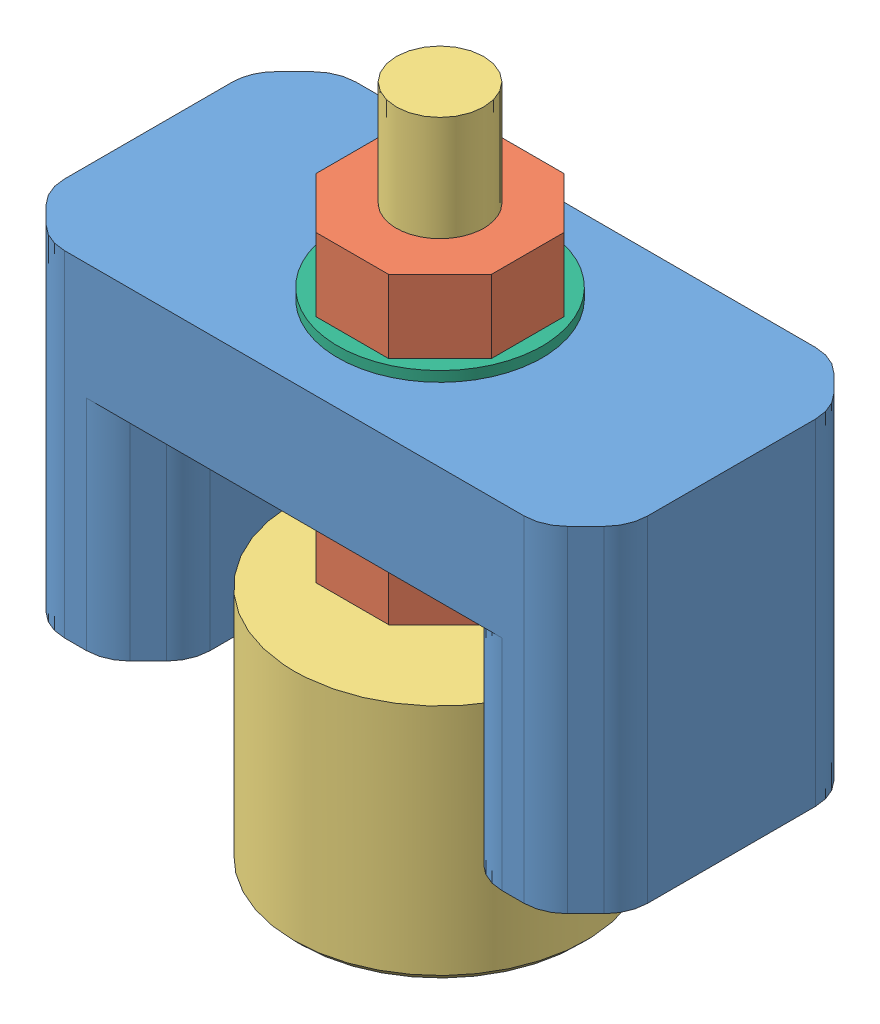
SolidWorks assembly Assemblage Roue Porteuse, configuration Défaut. Lengths in mm.
Overall size (40 50.71 20).
11 component instances, 6 part files, 20 mates.
Components (placement in the parent):
- Support Bille porteuse-1: Support Bille porteuse [Défaut] at (1.9744 -30.0894 -26.9817) size (40 23 20)
- Ecrou M6-3: Ecrou M6 [Défaut] at (1.9744 -17.1894 -26.9817) x (1 0 0) z (0 -1 0) size (12 12 5)
- Ecrou M6-2: Ecrou M6 [Défaut] at (1.9744 -1.3894 -26.9817) x (1 0 0) z (0 -1 0) size (12 12 5)
- Bille porteuse ALWAYE D12_7-2: Bille porteuse ALWAYE D12_7 [Défaut] at (1.9744 -30.1894 -26.9817) size (20 46.5 20)
- Bille D12-2: Bille D12 [Défaut] at (1.9744 -38.8998 -26.9817) size (12 12 12)
- Insert M4-2: Insert M4 [Défaut] at (16.9744 -30.0894 -26.9817) x (-0.837169 0 -0.546944) z (0 1 0) size (7 7 8)
- Insert M4-3: Insert M4 [Défaut] at (-13.0256 -30.0894 -26.9817) x (-0.837169 0 -0.546944) z (0 1 0) size (7 7 8)
- Rondelle M6-6: Rondelle M6 [Défaut] at (1.9744 -17.1894 -26.9817) x (1 0 0) z (0 1 0) size (14 14 0.7)
- Rondelle M6-7: Rondelle M6 [Défaut] at (1.9744 -16.4894 -26.9817) x (1 0 0) z (0 1 0) size (14 14 0.7)
- Rondelle M6-5: Rondelle M6 [Défaut] at (1.9744 -15.7894 -26.9817) x (1 0 0) z (0 1 0) size (14 14 0.7)
- Rondelle M6-4: Rondelle M6 [Défaut] at (1.9744 -7.0894 -26.9817) x (1 0 0) z (0 1 0) size (14 14 0.7)
Mates (geometry in assembly coordinates):
- Coaxiale9: concentric: cylinder of Bille porteuse ALWAYE D12_7-2 through (1.9744 -40.1894 -26.9817) axis (0 1 0) radius 6.75; sphere of Bille D12-2
- Verrouiller1: lock: unknown of Bille porteuse ALWAYE D12_7-2; unknown of Bille D12-2
- Coaxiale10: concentric anti-aligned: cylinder of Ecrou M6-3 through (1.9744 -22.1894 -26.9817) axis (0 1 0) radius 3; cylinder of Bille porteuse ALWAYE D12_7-2 through (1.9744 5.8106 -26.9817) axis (0 -1 0) radius 3
- Coaxiale11: concentric anti-aligned: cylinder of Support Bille porteuse-1 through (1.9744 -17.0894 -26.9817) axis (0 1 0) radius 3.2; cylinder of Bille porteuse ALWAYE D12_7-2 through (1.9744 5.8106 -26.9817) axis (0 -1 0) radius 3
- Coaxiale12: concentric anti-aligned: cylinder of Ecrou M6-2 through (1.9744 -6.3894 -26.9817) axis (0 1 0) radius 3; cylinder of Bille porteuse ALWAYE D12_7-2 through (1.9744 5.8106 -26.9817) axis (0 -1 0) radius 3
- Coaxiale13: concentric aligned: cylinder of Support Bille porteuse-1 through (-13.0256 -23.0894 -26.9817) axis (0 -1 0) radius 2.75; cylinder of Insert M4-3 through (-13.0256 -22.0894 -26.9817) axis (0 -1 0) radius 2.75
- Coaxiale14: concentric aligned: cylinder of Support Bille porteuse-1 through (16.9744 -23.0894 -26.9817) axis (0 -1 0) radius 2.75; cylinder of Insert M4-2 through (16.9744 -22.0894 -26.9817) axis (0 -1 0) radius 2.75
- Coïncidente4: coincident anti-aligned: plane of Support Bille porteuse-1 through (1.9744 -29.0894 -26.9817) normal (0 -1 0); plane of Insert M4-2 through (16.9744 -29.0894 -26.9817) normal (0 1 0)
- Coïncidente5: coincident anti-aligned: plane of Support Bille porteuse-1 through (1.9744 -29.0894 -26.9817) normal (0 -1 0); plane of Insert M4-3 through (-13.0256 -29.0894 -26.9817) normal (0 1 0)
- Coïncidente6: coincident anti-aligned: plane of Rondelle M6-7 through (1.9744 -15.7894 -26.9817) normal (0 1 0); plane of Rondelle M6-5 through (1.9744 -15.7894 -26.9817) normal (0 -1 0)
- Coïncidente7: coincident anti-aligned: plane of Rondelle M6-6 through (1.9744 -16.4894 -26.9817) normal (0 1 0); plane of Rondelle M6-7 through (1.9744 -16.4894 -26.9817) normal (0 -1 0)
- Coaxiale15: concentric aligned: cylinder of Rondelle M6-6 through (1.9744 -17.9894 -26.9817) axis (0 1 0) radius 3; cylinder of Rondelle M6-7 through (1.9744 -17.2894 -26.9817) axis (0 1 0) radius 3
- Coaxiale16: concentric aligned: cylinder of Rondelle M6-7 through (1.9744 -17.2894 -26.9817) axis (0 1 0) radius 3; cylinder of Rondelle M6-5 through (1.9744 -16.5894 -26.9817) axis (0 1 0) radius 3
- Coaxiale17: concentric anti-aligned: cylinder of Bille porteuse ALWAYE D12_7-2 through (1.9744 5.8106 -26.9817) axis (0 -1 0) radius 3; cylinder of Rondelle M6-7 through (1.9744 -17.2894 -26.9817) axis (0 1 0) radius 3
- Coïncidente9: coincident anti-aligned: plane of Support Bille porteuse-1 through (1.9744 -15.0894 -26.9817) normal (0 -1 0); plane of Rondelle M6-5 through (1.9744 -15.0894 -26.9817) normal (0 1 0)
- Coïncidente10: coincident anti-aligned: plane of Ecrou M6-3 through (1.9744 -17.1894 -26.9817) normal (0 1 0); plane of Rondelle M6-6 through (1.9744 -17.1894 -26.9817) normal (0 -1 0)
- Coïncidente11: coincident anti-aligned: plane of Support Bille porteuse-1 through (1.9744 -7.0894 -26.9817) normal (0 1 0); plane of Rondelle M6-4 through (1.9744 -7.0894 -26.9817) normal (0 -1 0)
- Coaxiale18: concentric anti-aligned: cylinder of Bille porteuse ALWAYE D12_7-2 through (1.9744 5.8106 -26.9817) axis (0 -1 0) radius 3; cylinder of Rondelle M6-4 through (1.9744 -7.8894 -26.9817) axis (0 1 0) radius 3
- Coïncidente12: coincident anti-aligned: plane of Ecrou M6-2 through (1.9744 -6.3894 -26.9817) normal (0 -1 0); plane of Rondelle M6-4 through (1.9744 -6.3894 -26.9817) normal (0 1 0)
- Distance1: distance = 2 mm anti-aligned: plane of Bille porteuse ALWAYE D12_7-2 through (1.9744 -24.1894 -26.9817) normal (0 1 0); plane of Ecrou M6-3 through (1.9744 -22.1894 -26.9817) normal (0 -1 0)
